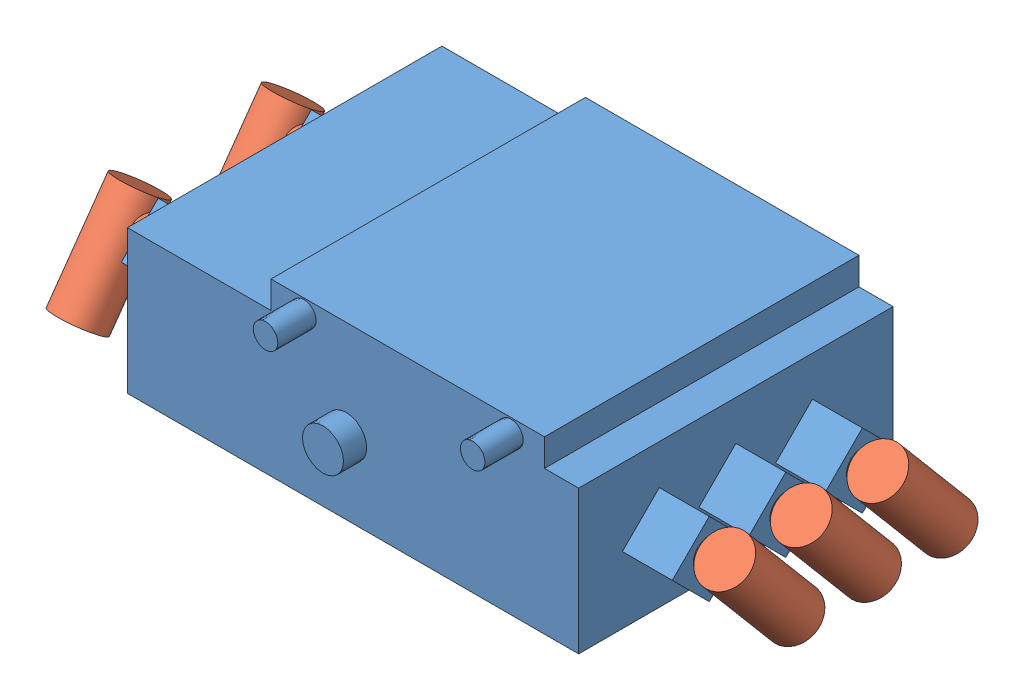
SolidWorks assembly Bamocar + pfisterer, configuration Default. Lengths in mm.
Overall size (486 132.1 258).
6 component instances, 2 part files, 5 mates.
Components (placement in the parent):
- BamoCar-1: BamoCar [Default] at (-49.5759 31.0269 -130.7125) size (403 125 258)
- Pfisterer Elbow-5: Pfisterer Elbow [Default] at (175.4241 44.9367 -59.5256) x (-1 0 0) z (0 -0.764279 -0.644886) size (75 36 78.5)
- Pfisterer Elbow-6: Pfisterer Elbow [Default] at (175.4241 44.9367 -3.5256) x (-1 0 0) z (0 -0.764279 -0.644886) size (75 36 78.5)
- Pfisterer Elbow-7: Pfisterer Elbow [Default] at (175.4241 44.9367 52.4744) x (-1 0 0) z (0 -0.764279 -0.644886) size (75 36 78.5)
- Pfisterer Elbow-11: Pfisterer Elbow [Default] at (-274.5759 45.8717 -81.792) x (1 0 0) z (0 -0.815652 0.578543) size (75 36 78.5)
- Pfisterer Elbow-14: Pfisterer Elbow [Default] at (-274.5759 45.8717 30.208) x (1 0 0) z (0 -0.815652 0.578543) size (75 36 78.5)
Mates (geometry in assembly coordinates):
- Distance2: distance = 3 mm anti-aligned: plane of BamoCar-1 through (115.4241 83.5269 99.2875) normal (1 0 0); plane of Pfisterer Elbow-5 through (118.4241 31.0269 -71.2625) normal (-1 0 0)
- Concentric2: concentric anti-aligned: cylinder of Pfisterer Elbow-5 through (118.4241 31.0269 -71.2625) axis (1 0 0) radius 11.15; cylinder of Pfisterer Elbow-11 through (-217.5759 31.0269 -71.2625) axis (-1 0 0) radius 11.15
- Distance3: distance = 3 mm anti-aligned: plane of BamoCar-1 through (-214.5759 83.5269 99.2875) normal (-1 0 0); plane of Pfisterer Elbow-11 through (-217.5759 31.0269 -71.2625) normal (1 0 0)
- Concentric3: concentric anti-aligned: cylinder of Pfisterer Elbow-5 through (118.4241 31.0269 -71.2625) axis (1 0 0) radius 11.15; cylinder of Pfisterer Elbow-11 through (-217.5759 31.0269 -71.2625) axis (-1 0 0) radius 11.15
- Concentric4: concentric: point of BamoCar-1; cylinder of Pfisterer Elbow-7 through (118.5241 31.0269 40.7375) axis (1 0 0) radius 11.15
